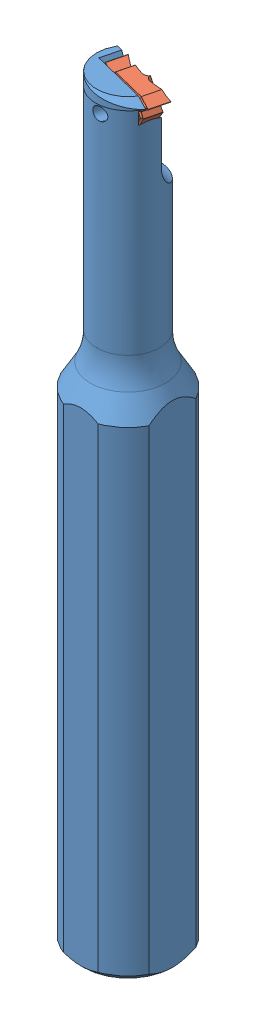
SolidWorks assembly Suporte com, configuration Valor predeterminado. Lengths in mm.
Overall size (16.86 123.8 15.02).
2 component instances, 2 part files, 2 mates.
Components (placement in the parent):
- Suporte Rosca-1: Suporte Rosca [Valor predeterminado] at (6.9327 -60.6062 120) size (15.07 120 15.02)
- Pastilha Rosca 11mm-1: Pastilha Rosca 11mm [Valor predeterminado] at (8.1504 56.2184 121.8495) x (-0.485148 0.866025 -0.120961) z (0.241922 0 -0.970296) size (9.39 8.59 3.2)
Mates (geometry in assembly coordinates):
- Coincidente1: coincident aligned: plane of Suporte Rosca-1 through (11.9327 59.3938 120) normal (0 1 0); plane of Pastilha Rosca 11mm-1 through (14.2611 59.3938 120.0751) normal (0 1 0)
- Distância1: distance = 0.2 mm aligned: plane of Pastilha Rosca 11mm-1 through (8.9245 56.2184 118.7446) normal (0.241922 0 -0.970296); plane of Suporte Rosca-1 through (1.1003 44.3938 116.9999) normal (0.241922 0 -0.970296)
